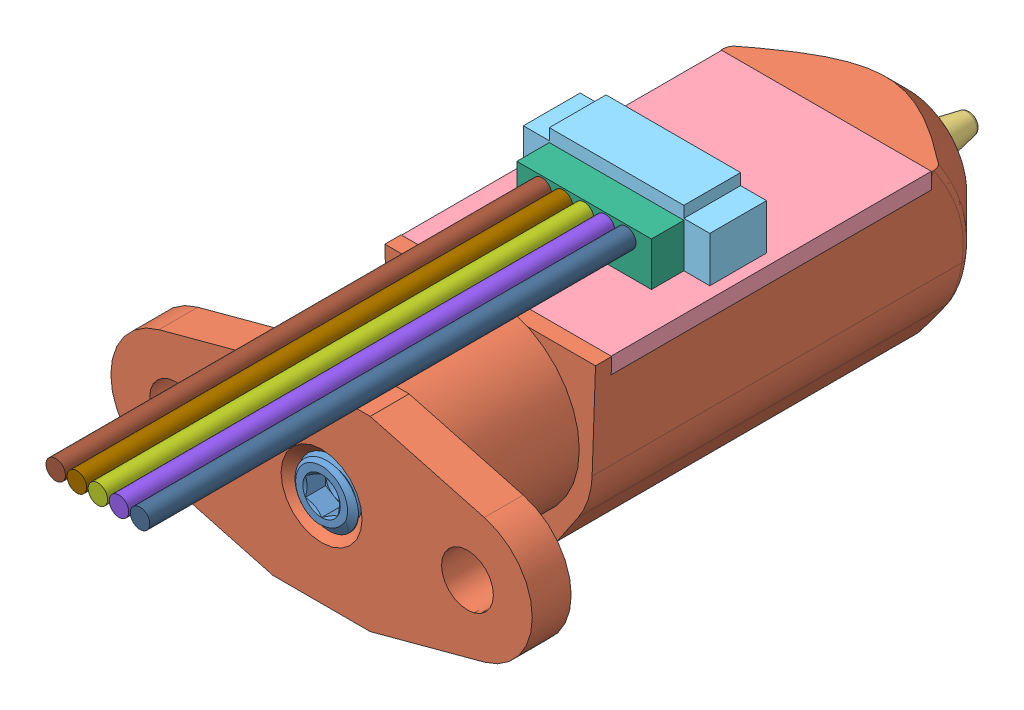
SolidWorks assembly BLTouch-Smart V3.1.step, configuration Default. Lengths in mm.
Overall size (26 15.35 53.8).
11 component instances, 11 part files, 0 mates.
Components (placement in the parent):
- 93245A111.step-1: 93245A111.step [Default] at (0 0 -2.4994) size (4.89 4.75 5.01)
- BL-touch.step-1: BL-touch.step [Default] at origin size (26 12.6 36.68)
- BL-touch-0.step-1: BL-touch-0.step [Default] at origin size (2.08 2.08 10)
- BL-touch-1.step-1: BL-touch-1.step [Default] at origin size (12.93 1 19.75)
- BL-touch-2.step-1: BL-touch-2.step [Default] at origin size (11.5 3.5 3.5)
- BL-touch-3.step-1: BL-touch-3.step [Default] at origin size (8.3 2.7 2)
- BL-touch-4.step-1: BL-touch-4.step [Default] at origin size (1.2 1.2 30)
- BL-touch-5.step-1: BL-touch-5.step [Default] at origin size (1.2 1.2 30)
- BL-touch-6.step-1: BL-touch-6.step [Default] at origin size (1.2 1.2 30)
- BL-touch-7.step-1: BL-touch-7.step [Default] at origin size (1.2 1.2 30)
- BL-touch-8.step-1: BL-touch-8.step [Default] at origin size (1.2 1.2 30)
